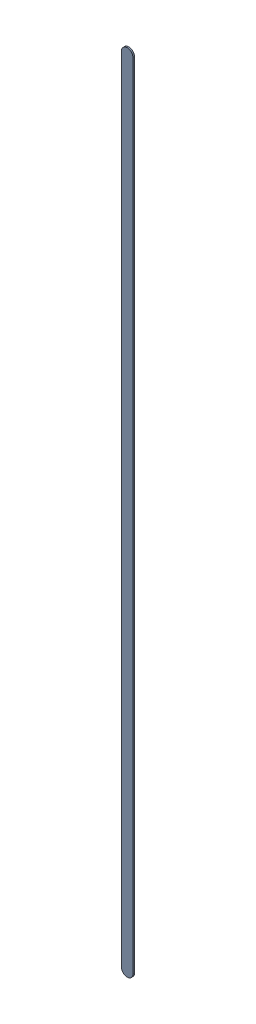
SolidWorks assembly Track (7.2mm,32mm)(7.2mm,49.6mm) on Bottom Layer, configuration Predeterminado. Lengths in mm.
Overall size (0.25 17.85 0.04).
2 component instances, 1 part files, 0 mates.
Components (placement in the parent):
- Track (7.2mm,32mm)(7.2mm,49.6mm) on Bottom Layer-1-1: Track (7.2mm,32mm)(7.2mm,49.6mm) on Bottom Layer-1 [Predeterminado] at (-68.317 -44.187 -0.4013) size (0.25 17.85 0.04)
  - Track (7.2mm,32mm)(7.2mm,49.6mm) on Bottom Layer-Part-1-1: Track (7.2mm,32mm)(7.2mm,49.6mm) on Bottom Layer-Part-1 [Predeterminado] at origin size (0.25 17.85 0.04)
